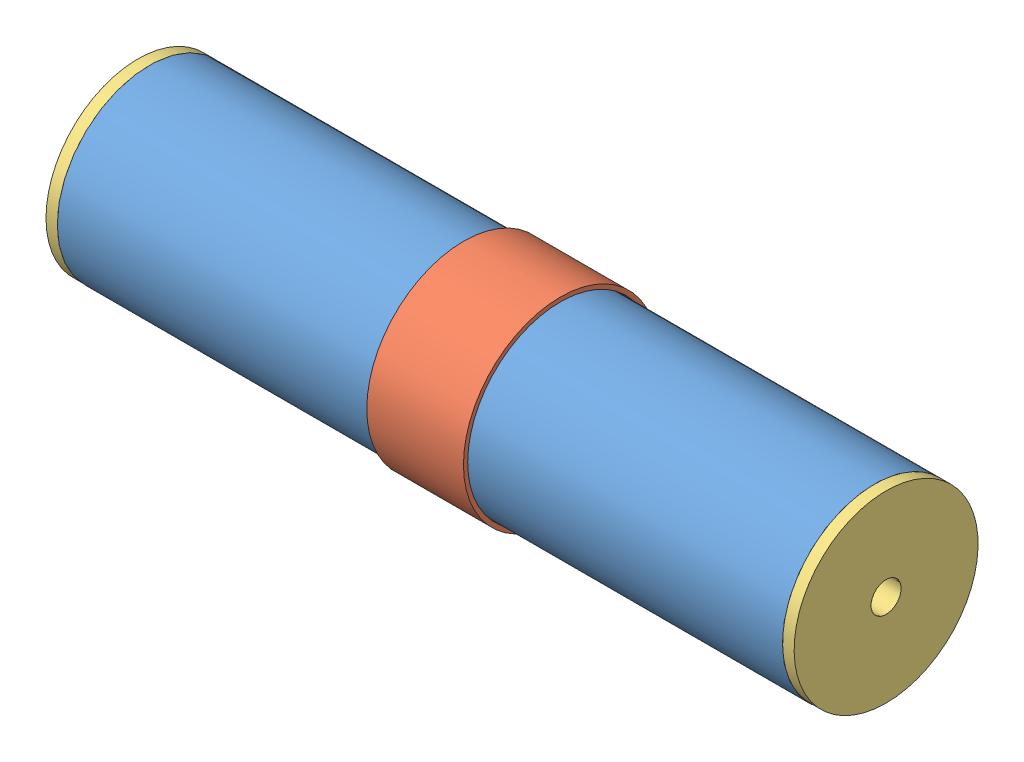
SolidWorks assembly ElectronicsBay, configuration Default. Lengths in mm.
Overall size (157.23 50.58 50.58).
4 component instances, 3 part files, 6 mates.
Components (placement in the parent):
- 6inFiberglassCoupler-1: 6inFiberglassCoupler [Default] at (-36.3446 -5.3728 -17.381) size (152.4 38.76 38.76)
- 08InThinWallFiberglass-1: 08InThinWallFiberglass [Default] at (29.6954 -5.3728 -17.381) size (20.32 40.74 40.74)
- EBayBulkhead-1: EBayBulkhead [Default] at (-38.7576 -5.3728 -17.381) size (5.08 38.66 38.66)
- EBayBulkhead-2: EBayBulkhead [Default] at (118.4684 -5.3728 -17.381) x (-1 0 0) z (0 -0.385815 -0.922576) size (5.08 38.66 38.66)
Mates (geometry in assembly coordinates):
- Concentric1: concentric aligned: cylinder of 6inFiberglassCoupler-1 through (116.0554 -5.3728 -17.381) axis (-1 0 0) radius 19.3802; cylinder of 08InThinWallFiberglass-1 through (50.0154 -5.3728 -17.381) axis (-1 0 0) radius 19.4818
- Distance1: distance = 66.04 mm aligned: plane of 08InThinWallFiberglass-1 through (50.0154 -5.3728 -17.381) normal (1 0 0); plane of 6inFiberglassCoupler-1 through (116.0554 -5.3728 -17.381) normal (1 0 0)
- Concentric2: concentric anti-aligned: cylinder of 6inFiberglassCoupler-1 through (116.0554 -5.3728 -17.381) axis (-1 0 0) radius 17.5514; cylinder of EBayBulkhead-1 through (-36.3446 -5.3728 -17.381) axis (1 0 0) radius 17.399
- Coincident2: coincident anti-aligned: plane of 6inFiberglassCoupler-1 through (-36.3446 -5.3728 -17.381) normal (-1 0 0); plane of EBayBulkhead-1 through (-36.3446 -5.3728 -17.381) normal (1 0 0)
- Concentric3: concentric aligned: cylinder of 6inFiberglassCoupler-1 through (116.0554 -5.3728 -17.381) axis (-1 0 0) radius 17.5514; cylinder of EBayBulkhead-2 through (116.0554 -5.3728 -17.381) axis (-1 0 0) radius 17.399
- Coincident4: coincident anti-aligned: plane of 6inFiberglassCoupler-1 through (116.0554 -5.3728 -17.381) normal (1 0 0); plane of EBayBulkhead-2 through (116.0554 -5.3728 -17.381) normal (-1 0 0)
